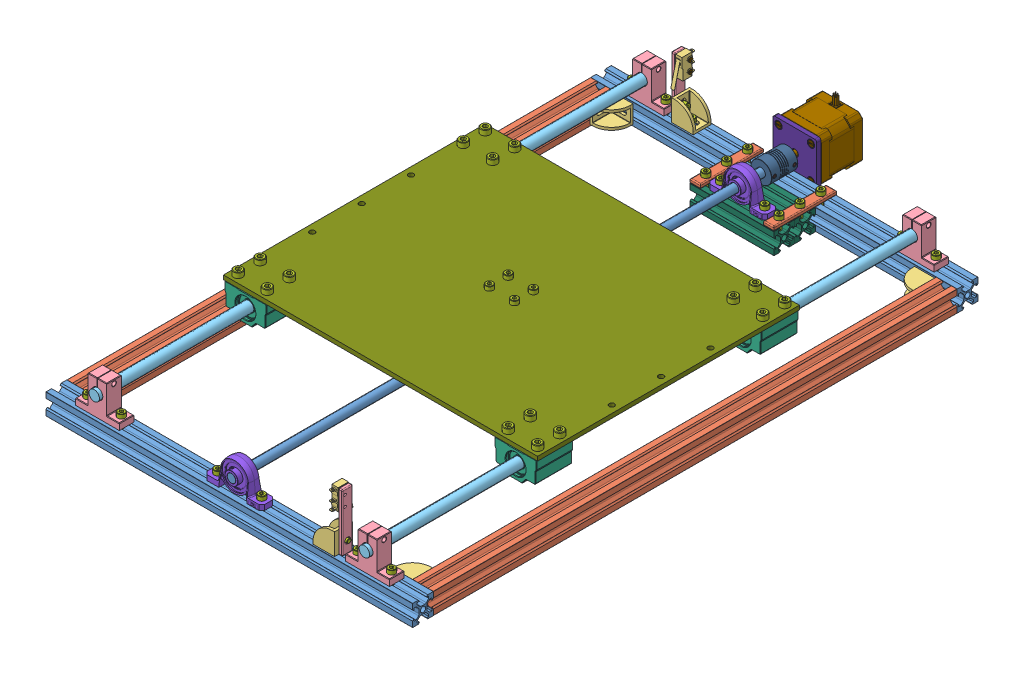
SolidWorks assembly eixoy_assembly, configuration Default. Lengths in mm.
94 component instances, 22 part files, 210 mates.
Components (placement in the parent):
- eixoy_frontal-1: eixoy_frontal [Valor predeterminado] at (179.0484 0.1053 350) x (0 0 -1) z (-1 0 0) size (20 20 350)
- eixoy_frontal-2: eixoy_frontal [Valor predeterminado] at (-170.9516 0.1053 870) x (0 0 -1) z (1 0 0) size (20 20 350)
- eixoy_lateral-1: eixoy_lateral [Valor predeterminado] at (-160.9516 0.1053 360) size (20 20 500)
- eixoy_lateral-2: eixoy_lateral [Valor predeterminado] at (169.0484 0.1053 360) size (20 20 500)
- cantoneira_perfil_2020-1: cantoneira_perfil_2020 [Varsayılan] at (-150.9516 0.1053 360) x (1 0 0) z (0 -1 0) size (20.5 20.5 17)
- cantoneira_perfil_2020-2: cantoneira_perfil_2020 [Varsayılan] at (-150.9516 0.1053 860) x (1 0 0) z (0 1 0) size (20.5 20.5 17)
- cantoneira_perfil_2020-3: cantoneira_perfil_2020 [Varsayılan] at (159.0484 0.1053 360) x (-1 0 0) z (0 1 0) size (20.5 20.5 17)
- cantoneira_perfil_2020-4: cantoneira_perfil_2020 [Varsayılan] at (159.0484 0.1053 860) x (-1 0 0) z (0 -1 0) size (20.5 20.5 17)
- suporte_guia_sk10-1: suporte_guia_sk10 [Default] at (-133.5305 19.8513 863) size (42 32.8 14)
- suporte_guia_sk10-2: suporte_guia_sk10 [Default] at (124.4695 19.8513 863) size (42 32.8 14)
- suporte_guia_sk10-3: suporte_guia_sk10 [Default] at (-133.5305 19.8513 343) size (42 32.8 14)
- suporte_guia_sk10-4: suporte_guia_sk10 [Default] at (124.4695 19.8513 343) size (42 32.8 14)
- eixoy_eixo_linear-1: eixoy_eixo_linear [Default] at (-124.9516 30.1053 340) x (0.995612 0.093577 0) z (0 0 1) size (10 10 540)
- eixoy_eixo_linear-2: eixoy_eixo_linear [Default] at (133.0484 30.1053 340) x (-0.037969 0.999279 0) z (0 0 1) size (10 10 540)
- pillow_block_sc10uu-1: pillow_block_sc10uu [По умолчанию] at (-124.9516 30.1053 718.0563) x (-1 0 0) z (0 0 1) size (40 26 35)
- pillow_block_sc10uu-2: pillow_block_sc10uu [По умолчанию] at (133.0484 30.1053 503.0563) x (-1 0 0) z (0 0 1) size (40 26 35)
- pillow_block_sc10uu-3: pillow_block_sc10uu [По умолчанию] at (-124.9516 30.1053 503.0563) x (-1 0 0) z (0 0 1) size (40 26 35)
- pillow_block_sc10uu-4: pillow_block_sc10uu [По умолчанию] at (133.0484 30.1053 718.0563) x (-1 0 0) z (0 0 1) size (40 26 35)
- socket head cap screw_am-1: socket head cap screw_am [B18.3.1M - 4 x 0.7 x 10 Hex SHCS -- 10NHX] at (117.0484 20.1053 870) x (0 -1 0) z (0 0 1) size (14 7 7)
- socket head cap screw_am-2: socket head cap screw_am [B18.3.1M - 4 x 0.7 x 10 Hex SHCS -- 10NHX] at (149.0484 20.1053 870) x (0 -1 0) z (0 0 1) size (14 7 7)
- socket head cap screw_am-3: socket head cap screw_am [B18.3.1M - 4 x 0.7 x 10 Hex SHCS -- 10NHX] at (-108.9516 20.1053 870) x (0 -1 0) z (0 0 1) size (14 7 7)
- socket head cap screw_am-4: socket head cap screw_am [B18.3.1M - 4 x 0.7 x 10 Hex SHCS -- 10NHX] at (-108.9516 20.1053 350) x (0 -1 0) z (0 0 1) size (14 7 7)
- socket head cap screw_am-5: socket head cap screw_am [B18.3.1M - 4 x 0.7 x 10 Hex SHCS -- 10NHX] at (149.0484 20.1053 350) x (0 -1 0) z (0 0 1) size (14 7 7)
- socket head cap screw_am-6: socket head cap screw_am [B18.3.1M - 4 x 0.7 x 10 Hex SHCS -- 10NHX] at (-140.9516 20.1053 870) x (0 -1 0) z (0 0 1) size (14 7 7)
- socket head cap screw_am-7: socket head cap screw_am [B18.3.1M - 4 x 0.7 x 10 Hex SHCS -- 10NHX] at (117.0484 20.1053 350) x (0 -1 0) z (0 0 1) size (14 7 7)
- socket head cap screw_am-8: socket head cap screw_am [B18.3.1M - 4 x 0.7 x 10 Hex SHCS -- 10NHX] at (-140.9516 20.1053 350) x (0 -1 0) z (0 0 1) size (14 7 7)
- Pillow Block P08-1: Pillow Block P08 [Default] at (4.0484 25.1053 389.6302) size (55 39.88 14.5)
- Pillow Block P08-2: Pillow Block P08 [Default] at (4.0484 25.1053 870) size (55 39.88 14.5)
- motor_nema17_40mm-1: motor_nema17_40mm [По умолчанию] at (4.0484 25.1053 296) x (-1 0 0) z (0 1 0) size (42.3 62 51.35)
- Acople Flexible-1: Acople Flexible [Predeterminado] at (3.1486 26.4664 347) x (-0.025514 0.999674 0) z (0 0 1) size (20.77 20.77 25)
  - Acople FlexibleSLDPRT-1: Acople FlexibleSLDPRT [Predeterminado] at (-1.3837 -0.8648 0) size (20.77 20.77 25)
  - socket set screw cone point_am-7: socket set screw cone point_am [B18.3.6M - M3 x 0.5 x 6 Hex Socket Cone Pt. SS --N] at (-11.2647 -0.8648 22) x (1 0 0) z (0 -0.164849 0.986319) size (6 3 3)
  - socket set screw cone point_am-8: socket set screw cone point_am [B18.3.6M - M3 x 0.5 x 6 Hex Socket Cone Pt. SS --N] at (-11.1909 -0.8648 3) x (1 0 0) z (0 0.00677 0.999977) size (6 3 3)
  - socket set screw cone point_am-9: socket set screw cone point_am [B18.3.6M - M3 x 0.5 x 6 Hex Socket Cone Pt. SS --N] at (-1.3837 -10.7654 3) x (0 1 0) z (-0.345086 0 0.938571) size (6 3 3)
  - socket set screw cone point_am-10: socket set screw cone point_am [B18.3.6M - M3 x 0.5 x 6 Hex Socket Cone Pt. SS --N] at (-1.3837 -10.5992 22) x (0 1 0) z (-0.865685 0 0.500588) size (6 3 3)
- castanha_tr8_2mm-1: castanha_tr8_2mm [Valor predeterminado] at (4.0484 25.1053 599.5563) x (-0.751873 0.659308 0) z (-0.659308 -0.751873 0) size (22 13.71 22)
- suporte_castanha_tr8-1: suporte_castanha_tr8 [Default] at (-13.4516 11.1053 625.5563) x (1 0 0) z (0 1 0) size (35 30 28)
- eixoy_espacador_castanha-1: eixoy_espacador_castanha [Default] at (-13.4516 39.1053 625.5563) x (1 0 0) z (0 1 0) size (35 30 4)
- eixoy_perfil_suporte_mancal-1: eixoy_perfil_suporte_mancal [Valor predeterminado] at (-35.9516 0.1053 370) x (0 0 -1) z (1 0 0) size (20 20 80)
- eixoy_mesa-1: eixoy_mesa [Default] at (154.0484 47.1053 735.5563) x (-1 0 0) z (0 -1 0) size (300 250 4)
- socket head cap screw_am-10: socket head cap screw_am [B18.3.1M - 4 x 0.7 x 10 Hex SHCS -- 10NHX] at (-6.4516 0.1053 332) x (0 0 1) z (1 0 0) size (14 7 7)
- socket head cap screw_am-11: socket head cap screw_am [B18.3.1M - 4 x 0.7 x 10 Hex SHCS -- 10NHX] at (14.5484 0.1053 332) x (0 0 1) z (-1 0 0) size (14 7 7)
- eixoy_suporte_motor-3: eixoy_suporte_motor [Default] at (25.0484 -9.8947 340) x (-1 0 0) z (0 0 -1) size (42 56 4)
- flat head screw_am-1: flat head screw_am [B18.6.7M - M3 x 0.5 x 8 Slotted FHMS --8N] at (-11.4516 9.6053 340) x (0 0 -1) z (1 0 0) size (8 5.5 5.41)
- flat head screw_am-2: flat head screw_am [B18.6.7M - M3 x 0.5 x 8 Slotted FHMS --8N] at (-11.4516 40.6053 340) x (0 0 -1) z (1 0 0) size (8 5.5 5.41)
- flat head screw_am-3: flat head screw_am [B18.6.7M - M3 x 0.5 x 8 Slotted FHMS --8N] at (19.5484 9.6053 340) x (0 0 -1) z (1 0 0) size (8 5.5 5.41)
- flat head screw_am-4: flat head screw_am [B18.6.7M - M3 x 0.5 x 8 Slotted FHMS --8N] at (19.5484 40.6053 340) x (0 0 -1) z (1 0 0) size (8 5.5 5.41)
- eixoy_perfil_suporte_mancal-2: eixoy_perfil_suporte_mancal [Valor predeterminado] at (-35.9516 0.1053 390) x (0 0 -1) z (1 0 0) size (20 20 80)
- eixoy_fuso-1: eixoy_fuso [Default] at (4.0484 25.1053 365.95) x (-0.063938 0.997954 0) z (0 0 1) size (8 8 512)
- eixoy_chapa_suporte_mancal-1: eixoy_chapa_suporte_mancal [Default] at (-35.9516 14.1053 340) x (1 0 0) z (0 -1 0) size (10 60 4)
- eixoy_chapa_suporte_mancal-2: eixoy_chapa_suporte_mancal [Default] at (34.0484 14.1053 340) x (1 0 0) z (0 -1 0) size (10 60 4)
- socket head cap screw_am-12: socket head cap screw_am [B18.3.1M - 4 x 0.7 x 10 Hex SHCS -- 10NHX] at (25.0484 19.1053 389.6302) x (0 -1 0) z (0 0 1) size (14 7 7)
- socket head cap screw_am-13: socket head cap screw_am [B18.3.1M - 4 x 0.7 x 10 Hex SHCS -- 10NHX] at (39.0484 18.1053 350) x (0 -1 0) z (-0.924225 0 0.381849) size (14 7 7)
- socket head cap screw_am-14: socket head cap screw_am [B18.3.1M - 4 x 0.7 x 10 Hex SHCS -- 10NHX] at (-30.9516 18.1053 350) x (0 -1 0) z (0 0 1) size (14 7 7)
- socket head cap screw_am-15: socket head cap screw_am [B18.3.1M - 4 x 0.7 x 10 Hex SHCS -- 10NHX] at (39.0484 18.1053 390) x (0 -1 0) z (0 0 1) size (14 7 7)
- socket head cap screw_am-16: socket head cap screw_am [B18.3.1M - 4 x 0.7 x 10 Hex SHCS -- 10NHX] at (39.0484 18.1053 370) x (0 -1 0) z (0 0 1) size (14 7 7)
- socket head cap screw_am-17: socket head cap screw_am [B18.3.1M - 4 x 0.7 x 10 Hex SHCS -- 10NHX] at (-16.9516 19.1053 389.6302) x (0 -1 0) z (0 0 1) size (14 7 7)
- socket head cap screw_am-18: socket head cap screw_am [B18.3.1M - 4 x 0.7 x 10 Hex SHCS -- 10NHX] at (-30.9516 18.1053 390) x (0 -1 0) z (0 0 1) size (14 7 7)
- socket head cap screw_am-19: socket head cap screw_am [B18.3.1M - 4 x 0.7 x 10 Hex SHCS -- 10NHX] at (-30.9516 18.1053 370) x (0 -1 0) z (0 0 1) size (14 7 7)
- socket head cap screw_am-20: socket head cap screw_am [B18.3.1M - 4 x 0.7 x 10 Hex SHCS -- 10NHX] at (25.0484 19.1053 870) x (0 -1 0) z (0 0 1) size (14 7 7)
- socket head cap screw_am-21: socket head cap screw_am [B18.3.1M - 4 x 0.7 x 10 Hex SHCS -- 10NHX] at (-16.9516 19.1053 870) x (0 -1 0) z (0 0 1) size (14 7 7)
- switch_fim_de_curso_KW11-3Z-5-2: switch_fim_de_curso_KW11-3Z-5 [Default] at (96.8484 45.2053 875.4) x (0 1 0) z (0 0 -1) size (25.09 6.4 19.9)
- eixoy_suporte_fim_curso-1: eixoy_suporte_fim_curso [Default] at (-94.9516 65.1053 355) x (0 0 -1) z (-1 0 0) size (10 55 4)
- switch_fim_de_curso_KW11-3Z-5-3: switch_fim_de_curso_KW11-3Z-5 [Default] at (-88.7516 45.2053 344.6) x (0 1 0) z (0 0 1) size (25.09 6.4 19.9)
- flat head screw_am-5: flat head screw_am [B18.6.7M - M2 x 0.4 x 10 Slotted FHMS --10N] at (-87.5516 50.2053 347.6) x (-1 0 0) z (0 0.022385 0.999749) size (10 3.8 3.73)
- flat head screw_am-6: flat head screw_am [B18.6.7M - M2 x 0.4 x 10 Slotted FHMS --10N] at (-87.5516 60.1053 347.6) x (-1 0 0) z (0 -0.689904 -0.723901) size (10 3.8 3.73)
- cantoneira_perfil_2020-5: cantoneira_perfil_2020 [Varsayılan] at (-94.9516 10.1053 350) size (20.5 20.5 17)
- socket head cap screw_am-22: socket head cap screw_am [B18.3.1M - 4 x 0.7 x 10 Hex SHCS -- 10NHX] at (-84.0639 16.6053 350.75) x (0 -1 0) z (-0.654967 0 0.755658) size (14 7 7)
- socket head cap screw_am-23: socket head cap screw_am [B18.3.1M - 4 x 0.7 x 8 Hex SHCS -- 8NHX] at (-88.4516 21.3124 350) x (-1 0 0) z (0 0 1) size (12 7 7)
- eixoy_suporte_fim_curso-2: eixoy_suporte_fim_curso [Default] at (103.0484 65.1053 865) x (0 0 1) z (1 0 0) size (10 55 4)
- flat head screw_am-7: flat head screw_am [B18.6.7M - M2 x 0.4 x 10 Slotted FHMS --10N] at (95.6484 50.2053 872.4) size (10 3.8 3.73)
- flat head screw_am-8: flat head screw_am [B18.6.7M - M2 x 0.4 x 10 Slotted FHMS --10N] at (95.6484 60.1053 872.4) x (1 0 0) z (0 0.537114 0.843509) size (10 3.8 3.73)
- cantoneira_perfil_2020-6: cantoneira_perfil_2020 [Varsayılan] at (103.0484 10.1053 870) x (-1 0 0) z (0 0 -1) size (20.5 20.5 17)
- socket head cap screw_am-25: socket head cap screw_am [B18.3.1M - 4 x 0.7 x 8 Hex SHCS -- 8NHX] at (96.5484 21.3124 870) size (12 7 7)
- socket head cap screw_am-28: socket head cap screw_am [B18.3.1M - 5 x 0.8 x 10 Hex SHCS -- 10NHX] at (-110.9516 52.1053 707.5563) x (0 -1 0) z (0 0 1) size (15 8.5 8.5)
- socket head cap screw_am-29: socket head cap screw_am [B18.3.1M - 5 x 0.8 x 10 Hex SHCS -- 10NHX] at (-110.9516 52.1053 728.5563) x (0 -1 0) z (0 0 1) size (15 8.5 8.5)
- socket head cap screw_am-30: socket head cap screw_am [B18.3.1M - 5 x 0.8 x 10 Hex SHCS -- 10NHX] at (-138.9516 52.1053 707.5563) x (0 -1 0) z (0 0 1) size (15 8.5 8.5)
- socket head cap screw_am-31: socket head cap screw_am [B18.3.1M - 5 x 0.8 x 10 Hex SHCS -- 10NHX] at (-138.9516 52.1053 728.5563) x (0 -1 0) z (0 0 1) size (15 8.5 8.5)
- socket head cap screw_am-32: socket head cap screw_am [B18.3.1M - 5 x 0.8 x 10 Hex SHCS -- 10NHX] at (119.0484 52.1053 707.5563) x (0 -1 0) z (0 0 1) size (15 8.5 8.5)
- socket head cap screw_am-33: socket head cap screw_am [B18.3.1M - 5 x 0.8 x 10 Hex SHCS -- 10NHX] at (119.0484 52.1053 728.5563) x (0 -1 0) z (0 0 1) size (15 8.5 8.5)
- socket head cap screw_am-34: socket head cap screw_am [B18.3.1M - 5 x 0.8 x 10 Hex SHCS -- 10NHX] at (147.0484 52.1053 728.5563) x (0 -1 0) z (0 0 1) size (15 8.5 8.5)
- socket head cap screw_am-35: socket head cap screw_am [B18.3.1M - 5 x 0.8 x 10 Hex SHCS -- 10NHX] at (147.0484 52.1053 707.5563) x (0 -1 0) z (0 0 1) size (15 8.5 8.5)
- socket head cap screw_am-36: socket head cap screw_am [B18.3.1M - 5 x 0.8 x 10 Hex SHCS -- 10NHX] at (119.0484 52.1053 513.5563) x (0 -1 0) z (0 0 1) size (15 8.5 8.5)
- socket head cap screw_am-37: socket head cap screw_am [B18.3.1M - 5 x 0.8 x 10 Hex SHCS -- 10NHX] at (119.0484 52.1053 492.5563) x (0 -1 0) z (0 0 1) size (15 8.5 8.5)
- socket head cap screw_am-38: socket head cap screw_am [B18.3.1M - 5 x 0.8 x 10 Hex SHCS -- 10NHX] at (147.0484 52.1053 492.5563) x (0 -1 0) z (0 0 1) size (15 8.5 8.5)
- socket head cap screw_am-39: socket head cap screw_am [B18.3.1M - 5 x 0.8 x 10 Hex SHCS -- 10NHX] at (147.0484 52.1053 513.5563) x (0 -1 0) z (0 0 1) size (15 8.5 8.5)
- socket head cap screw_am-40: socket head cap screw_am [B18.3.1M - 5 x 0.8 x 10 Hex SHCS -- 10NHX] at (-138.9516 52.1053 492.5563) x (0 -1 0) z (0 0 1) size (15 8.5 8.5)
- socket head cap screw_am-41: socket head cap screw_am [B18.3.1M - 5 x 0.8 x 10 Hex SHCS -- 10NHX] at (-110.9516 52.1053 492.5563) x (0 -1 0) z (0 0 1) size (15 8.5 8.5)
- socket head cap screw_am-42: socket head cap screw_am [B18.3.1M - 5 x 0.8 x 10 Hex SHCS -- 10NHX] at (-110.9516 52.1053 513.5563) x (0 -1 0) z (0 0 1) size (15 8.5 8.5)
- socket head cap screw_am-43: socket head cap screw_am [B18.3.1M - 5 x 0.8 x 10 Hex SHCS -- 10NHX] at (-138.9516 52.1053 513.5563) x (0 -1 0) z (0 0 1) size (15 8.5 8.5)
- socket head cap screw_am-44: socket head cap screw_am [B18.3.1M - 4 x 0.7 x 8 Hex SHCS -- 8NHX] at (16.0484 51.1053 601.5563) x (0 -1 0) z (0 0 1) size (12 7 7)
- socket head cap screw_am-45: socket head cap screw_am [B18.3.1M - 4 x 0.7 x 8 Hex SHCS -- 8NHX] at (-7.9516 51.1053 601.5563) x (0 -1 0) z (0 0 1) size (12 7 7)
- socket head cap screw_am-46: socket head cap screw_am [B18.3.1M - 4 x 0.7 x 8 Hex SHCS -- 8NHX] at (-7.9516 51.1053 619.5563) x (0 -1 0) z (0 0 1) size (12 7 7)
- socket head cap screw_am-47: socket head cap screw_am [B18.3.1M - 4 x 0.7 x 8 Hex SHCS -- 8NHX] at (16.0484 51.1053 619.5563) x (0 -1 0) z (0 0 1) size (12 7 7)
Mates (geometry in assembly coordinates):
- Coincident1: coincident aligned: plane of eixoy_frontal-2 through (179.0484 10.1053 865.4) normal (0 1 0); plane of eixoy_lateral-1 through (-156.3516 10.1053 860) normal (0 1 0)
- Coincident2: coincident anti-aligned: plane of eixoy_frontal-2 through (179.0484 9.9053 860) normal (0 0 -1); plane of eixoy_lateral-1 through (-164.5344 -8.5947 860) normal (0 0 1)
- Coincident3: coincident aligned: plane of eixoy_frontal-2 through (-170.9516 -8.5947 873.5828) normal (-1 0 0); plane of eixoy_lateral-1 through (-170.9516 9.9053 860) normal (-1 0 0)
- Coincident4: coincident aligned: plane of eixoy_frontal-2 through (179.0484 -8.5947 873.5828) normal (1 0 0); plane of eixoy_lateral-2 through (179.0484 9.9053 860) normal (1 0 0)
- Coincident5: coincident aligned: plane of eixoy_frontal-2 through (179.0484 10.1053 874.6) normal (0 1 0); plane of eixoy_lateral-2 through (173.6484 10.1053 860) normal (0 1 0)
- Coincident6: coincident anti-aligned: plane of eixoy_frontal-2 through (179.0484 9.9053 860) normal (0 0 -1); plane of eixoy_lateral-2 through (165.4656 -8.5947 860) normal (0 0 1)
- Coincident7: coincident anti-aligned: plane of eixoy_frontal-1 through (-170.9516 9.9053 360) normal (0 0 1); plane of eixoy_lateral-2 through (165.4656 -8.5947 360) normal (0 0 -1)
- Coincident8: coincident aligned: plane of eixoy_frontal-1 through (179.0484 8.8053 353.5828) normal (1 0 0); plane of eixoy_lateral-2 through (179.0484 9.9053 860) normal (1 0 0)
- Coincident9: coincident aligned: plane of eixoy_frontal-1 through (-170.9516 10.1053 354.6) normal (0 1 0); plane of eixoy_lateral-2 through (164.4484 10.1053 860) normal (0 1 0)
- Coincident10: coincident anti-aligned: plane of eixoy_lateral-1 through (-150.9516 9.9053 860) normal (1 0 0); plane of cantoneira_perfil_2020-1 through (-150.9516 -8.3947 360) normal (-1 0 0)
- Coincident11: coincident aligned: plane of cantoneira_perfil_2020-1 through (-150.9516 -8.3947 360) normal (-1 0 0); plane of cantoneira_perfil_2020-2 through (-150.9516 8.6053 860) normal (-1 0 0)
- Coincident12: coincident anti-aligned: plane of eixoy_frontal-2 through (179.0484 9.9053 860) normal (0 0 -1); plane of cantoneira_perfil_2020-2 through (-130.4516 8.6053 860) normal (0 0 1)
- Coincident13: coincident anti-aligned: plane of eixoy_frontal-1 through (-170.9516 9.9053 360) normal (0 0 1); plane of cantoneira_perfil_2020-1 through (-130.4516 -8.3947 360) normal (0 0 -1)
- Coincident14: coincident anti-aligned: plane of eixoy_lateral-2 through (159.0484 9.9053 860) normal (-1 0 0); plane of cantoneira_perfil_2020-3 through (159.0484 8.6053 360) normal (1 0 0)
- Coincident15: coincident anti-aligned: plane of eixoy_frontal-1 through (-170.9516 9.9053 360) normal (0 0 1); plane of cantoneira_perfil_2020-3 through (138.5484 8.6053 360) normal (0 0 -1)
- Coincident16: coincident aligned: plane of cantoneira_perfil_2020-1 through (-150.9516 8.6053 360) normal (0 1 0); plane of cantoneira_perfil_2020-3 through (159.0484 8.6053 360) normal (0 1 0)
- Coincident17: coincident aligned: plane of cantoneira_perfil_2020-1 through (-150.9516 8.6053 360) normal (0 1 0); plane of cantoneira_perfil_2020-2 through (-150.9516 8.6053 860) normal (0 1 0)
- Coincident19: coincident anti-aligned: plane of eixoy_frontal-2 through (179.0484 9.9053 860) normal (0 0 -1); plane of cantoneira_perfil_2020-4 through (138.5484 -8.3947 860) normal (0 0 1)
- Coincident20: coincident aligned: plane of cantoneira_perfil_2020-2 through (-150.9516 8.6053 860) normal (0 1 0); plane of cantoneira_perfil_2020-4 through (159.0484 8.6053 860) normal (0 1 0)
- Coincident21: coincident anti-aligned: plane of eixoy_lateral-2 through (159.0484 9.9053 860) normal (-1 0 0); plane of cantoneira_perfil_2020-4 through (159.0484 -8.3947 860) normal (1 0 0)
- Distance1: distance = 1.5 mm aligned: plane of cantoneira_perfil_2020-4 through (159.0484 8.6053 860) normal (0 1 0); plane of eixoy_lateral-2 through (164.4484 10.1053 860) normal (0 1 0)
- Concentric1: concentric anti-aligned: cylinder of suporte_guia_sk10-1 through (-124.9516 30.1053 863) axis (0 0 1) radius 5; cylinder of eixoy_eixo_linear-1 through (-124.9516 30.1053 880) axis (0 0 -1) radius 5
- Concentric2: concentric anti-aligned: cylinder of suporte_guia_sk10-3 through (-124.9516 30.1053 343) axis (0 0 1) radius 5; cylinder of eixoy_eixo_linear-1 through (-124.9516 30.1053 880) axis (0 0 -1) radius 5
- Concentric3: concentric anti-aligned: cylinder of suporte_guia_sk10-2 through (133.0484 30.1053 863) axis (0 0 1) radius 5; cylinder of eixoy_eixo_linear-2 through (133.0484 30.1053 880) axis (0 0 -1) radius 5
- Concentric4: concentric anti-aligned: cylinder of suporte_guia_sk10-4 through (133.0484 30.1053 343) axis (0 0 1) radius 5; cylinder of eixoy_eixo_linear-2 through (133.0484 30.1053 880) axis (0 0 -1) radius 5
- Distance2: distance = 3 mm aligned: plane of suporte_guia_sk10-1 through (-133.5305 19.8513 877) normal (0 0 1); plane of eixoy_frontal-2 through (179.0484 9.9053 880) normal (0 0 1)
- Coincident24: coincident anti-aligned: plane of eixoy_frontal-2 through (179.0484 10.1053 874.6) normal (0 1 0); plane of suporte_guia_sk10-1 through (-145.9516 10.1053 877) normal (0 -1 0)
- Coincident25: coincident aligned: plane of suporte_guia_sk10-4 through (112.0484 10.1053 357) normal (0 -1 0); plane of suporte_guia_sk10-2 through (112.0484 10.1053 877) normal (0 -1 0)
- Coincident26: coincident aligned: plane of suporte_guia_sk10-1 through (-133.5305 19.8513 877) normal (0 0 1); plane of suporte_guia_sk10-2 through (124.4695 19.8513 877) normal (0 0 1)
- Coincident27: coincident aligned: plane of suporte_guia_sk10-2 through (112.0484 10.1053 877) normal (0 -1 0); plane of suporte_guia_sk10-4 through (112.0484 10.1053 357) normal (0 -1 0)
- Coincident28: coincident aligned: plane of suporte_guia_sk10-3 through (-145.9516 10.1053 357) normal (0 -1 0); plane of suporte_guia_sk10-4 through (112.0484 10.1053 357) normal (0 -1 0)
- Coincident29: coincident aligned: plane of suporte_guia_sk10-1 through (-145.9516 10.1053 877) normal (0 -1 0); plane of suporte_guia_sk10-3 through (-145.9516 10.1053 357) normal (0 -1 0)
- Coincident30: coincident aligned: plane of suporte_guia_sk10-3 through (-133.5305 19.8513 343) normal (0 0 -1); plane of suporte_guia_sk10-4 through (124.4695 19.8513 343) normal (0 0 -1)
- Distance3: distance = 3 mm aligned: plane of suporte_guia_sk10-4 through (124.4695 19.8513 343) normal (0 0 -1); plane of eixoy_frontal-1 through (-170.9516 9.9053 340) normal (0 0 -1)
- Coincident32: coincident aligned: plane of eixoy_frontal-1 through (-170.9516 9.9053 340) normal (0 0 -1); plane of eixoy_eixo_linear-1 through (-124.9516 30.1053 340) normal (0 0 -1)
- Coincident33: coincident aligned: plane of eixoy_frontal-1 through (-170.9516 9.9053 340) normal (0 0 -1); plane of eixoy_eixo_linear-2 through (133.0484 30.1053 340) normal (0 0 -1)
- Distance5: distance = 25 mm aligned: plane of suporte_guia_sk10-1 through (-145.9516 16.1053 877) normal (-1 0 0); plane of eixoy_frontal-2 through (-170.9516 -8.5947 873.5828) normal (-1 0 0)
- Distance6: distance = 25 mm aligned: plane of suporte_guia_sk10-2 through (154.0484 16.1053 877) normal (1 0 0); plane of eixoy_frontal-2 through (179.0484 -8.5947 873.5828) normal (1 0 0)
- Coincident37: coincident aligned: plane of pillow_block_sc10uu-1 through (-113.5039 43.1053 735.5563) normal (0 1 0); plane of pillow_block_sc10uu-3 through (-113.5039 43.1053 520.5563) normal (0 1 0)
- Coincident38: coincident aligned: plane of pillow_block_sc10uu-3 through (-113.5039 43.1053 520.5563) normal (0 1 0); plane of pillow_block_sc10uu-4 through (144.4961 43.1053 735.5563) normal (0 1 0)
- Coincident39: coincident aligned: plane of pillow_block_sc10uu-2 through (144.4961 43.1053 520.5563) normal (0 1 0); plane of pillow_block_sc10uu-4 through (144.4961 43.1053 735.5563) normal (0 1 0)
- Concentric5: concentric aligned: cylinder of eixoy_eixo_linear-2 through (133.0484 30.1053 880) axis (0 0 -1) radius 5; cylinder of pillow_block_sc10uu-2 through (133.0484 30.1053 517.5563) axis (0 0 -1) radius 5
- Concentric6: concentric aligned: cylinder of eixoy_eixo_linear-2 through (133.0484 30.1053 880) axis (0 0 -1) radius 5; cylinder of pillow_block_sc10uu-4 through (133.0484 30.1053 732.5563) axis (0 0 -1) radius 5
- Concentric7: concentric aligned: cylinder of eixoy_eixo_linear-1 through (-124.9516 30.1053 880) axis (0 0 -1) radius 5; cylinder of pillow_block_sc10uu-1 through (-124.9516 30.1053 732.5563) axis (0 0 -1) radius 5
- Concentric8: concentric aligned: cylinder of eixoy_eixo_linear-1 through (-124.9516 30.1053 880) axis (0 0 -1) radius 5; cylinder of pillow_block_sc10uu-3 through (-124.9516 30.1053 517.5563) axis (0 0 -1) radius 5
- Coincident40: coincident aligned: plane of pillow_block_sc10uu-2 through (133.0484 30.1053 520.5563) normal (0 0 1); plane of pillow_block_sc10uu-3 through (-124.9516 30.1053 520.5563) normal (0 0 1)
- Coincident41: coincident aligned: plane of pillow_block_sc10uu-1 through (-124.9516 30.1053 700.5563) normal (0 0 -1); plane of pillow_block_sc10uu-4 through (133.0484 30.1053 700.5563) normal (0 0 -1)
- Coincident42: coincident aligned: plane of suporte_guia_sk10-1 through (-145.9516 16.1053 877) normal (0 1 0); circle of parafuso_allen_m4x10-1
- Coincident43: coincident aligned: plane of socket head cap screw_am-4 through (-105.4516 16.1053 350) normal (0 -1 0); plane of socket head cap screw_am-8 through (-137.4516 16.1053 350) normal (0 -1 0)
- Coincident44: coincident aligned: plane of socket head cap screw_am-4 through (-105.4516 16.1053 350) normal (0 -1 0); plane of socket head cap screw_am-7 through (120.5484 16.1053 350) normal (0 -1 0)
- Coincident45: coincident aligned: plane of socket head cap screw_am-5 through (152.5484 16.1053 350) normal (0 -1 0); plane of socket head cap screw_am-7 through (120.5484 16.1053 350) normal (0 -1 0)
- Coincident46: coincident aligned: plane of socket head cap screw_am-5 through (152.5484 16.1053 350) normal (0 -1 0); plane of socket head cap screw_am-6 through (-137.4516 16.1053 870) normal (0 -1 0)
- Coincident47: coincident aligned: plane of socket head cap screw_am-3 through (-105.4516 16.1053 870) normal (0 -1 0); plane of socket head cap screw_am-6 through (-137.4516 16.1053 870) normal (0 -1 0)
- Coincident48: coincident aligned: plane of socket head cap screw_am-2 through (152.5484 16.1053 870) normal (0 -1 0); plane of socket head cap screw_am-3 through (-105.4516 16.1053 870) normal (0 -1 0)
- Coincident49: coincident anti-aligned: plane of suporte_guia_sk10-2 through (142.0484 16.1053 877) normal (0 1 0); plane of socket head cap screw_am-2 through (152.5484 16.1053 870) normal (0 -1 0)
- Concentric9: concentric aligned: circle of suporte_guia_sk10-2; cylinder of socket head cap screw_am-2 through (149.0484 51.8553 870) axis (0 1 0) radius 2
- Concentric10: concentric aligned: circle of suporte_guia_sk10-2; cylinder of socket head cap screw_am-1 through (117.0484 51.8553 870) axis (0 1 0) radius 2
- Concentric11: concentric anti-aligned: cylinder of suporte_guia_sk10-1 through (-108.9516 35.1053 870) axis (0 -1 0) radius 2.5; cylinder of socket head cap screw_am-3 through (-108.9516 51.8553 870) axis (0 1 0) radius 2
- Concentric12: concentric anti-aligned: cylinder of suporte_guia_sk10-1 through (-140.9516 35.1053 870) axis (0 -1 0) radius 2.5; cylinder of socket head cap screw_am-6 through (-140.9516 51.8553 870) axis (0 1 0) radius 2
- Concentric13: concentric anti-aligned: cylinder of suporte_guia_sk10-4 through (149.0484 35.1053 350) axis (0 -1 0) radius 2.5; cylinder of socket head cap screw_am-5 through (149.0484 51.8553 350) axis (0 1 0) radius 2
- Concentric14: concentric aligned: circle of suporte_guia_sk10-4; cylinder of socket head cap screw_am-7 through (117.0484 51.8553 350) axis (0 1 0) radius 2
- Concentric15: concentric aligned: circle of suporte_guia_sk10-3; cylinder of socket head cap screw_am-4 through (-108.9516 51.8553 350) axis (0 1 0) radius 2
- Concentric16: concentric anti-aligned: cylinder of suporte_guia_sk10-3 through (-140.9516 35.1053 350) axis (0 -1 0) radius 2.5; cylinder of socket head cap screw_am-8 through (-140.9516 51.8553 350) axis (0 1 0) radius 2
- Distance7: distance = 250 mm anti-aligned: plane of pillow_block_sc10uu-2 through (133.0484 30.1053 485.5563) normal (0 0 -1); plane of pillow_block_sc10uu-4 through (133.0484 30.1053 735.5563) normal (0 0 1)
- Coincident52: coincident aligned: plane of Pillow Block P08-1 through (4.0484 10.1053 389.6302) normal (0 -1 0); plane of Pillow Block P08-2 through (4.0484 10.1053 870) normal (0 -1 0)
- Coincident53: coincident anti-aligned: plane of eixoy_frontal-1 through (-170.9516 10.1053 354.6) normal (0 1 0); plane of Pillow Block P08-1 through (4.0484 10.1053 389.6302) normal (0 -1 0)
- Distance9: distance = 3.5 mm aligned: plane of Pillow Block P08-2 through (4.0484 25.1053 876.5) normal (0 0 1); plane of eixoy_frontal-2 through (179.0484 9.9053 880) normal (0 0 1)
- Coincident56: coincident aligned: cylinder of motor_nema17_40mm-1 through (4.0484 25.1053 358) axis (0 0 -1) radius 2.5; circle of Acople Flexible-1/Acople FlexibleSLDPRT-1
- Distance10: distance = 4 mm: plane of Acople Flexible-1/Acople FlexibleSLDPRT-1 through (4.0484 25.1053 347) normal (0 0 -1); line of motor_nema17_40mm-1 through (1.6076 24.5645 343) axis (0.412738 0.91085 0)
- Concentric17: concentric anti-aligned: cylinder of Pillow Block P08-1 through (4.0484 25.1053 381.393) axis (0 0 -1) radius 4; cylinder of Acople Flexible-1/Acople FlexibleSLDPRT-1 through (4.0484 25.1053 354) axis (0 0 1) radius 4
- Coincident58: coincident aligned: plane of Pillow Block P08-1 through (-23.4516 25.1053 396.1302) normal (-1 0 0); plane of Pillow Block P08-2 through (-23.4516 25.1053 876.5) normal (-1 0 0)
- Distance11: distance = 147.5 mm aligned: plane of Pillow Block P08-2 through (31.5484 25.1053 876.5) normal (1 0 0); plane of eixoy_frontal-2 through (179.0484 -8.5947 873.5828) normal (1 0 0)
- Parallel1: parallel aligned: plane of eixoy_frontal-1 through (-170.9516 10.1053 354.6) normal (0 1 0); plane of motor_nema17_40mm-1 through (4.0484 46.1053 336) normal (0 1 0)
- Concentric18: concentric aligned: circle of Acople Flexible-1/Acople FlexibleSLDPRT-1; circle of castanha_tr8_2mm-1
- Concentric19: concentric anti-aligned: cylinder of castanha_tr8_2mm-1 through (4.0484 25.1053 609.5563) axis (0 0 -1) radius 5; cylinder of suporte_castanha_tr8-1 through (4.0484 25.1053 617.5563) axis (0 0 1) radius 7
- Parallel2: parallel aligned: cylinder of castanha_tr8_2mm-1 through (3.493 33.5721 609.5573) axis (0 0 -1) radius 1.75; cylinder of suporte_castanha_tr8-1 through (4.0484 33.1053 609.5563) axis (0 0 -1) radius 1.5
- Parallel3: parallel aligned: cylinder of castanha_tr8_2mm-1 through (4.6038 16.6385 609.5573) axis (0 0 -1) radius 1.75; cylinder of suporte_castanha_tr8-1 through (4.0484 17.1053 609.5563) axis (0 0 -1) radius 1.5
- Coincident60: coincident anti-aligned: plane of castanha_tr8_2mm-1 through (4.0484 25.1053 599.5563) normal (0 0 1); plane of suporte_castanha_tr8-1 through (4.0484 25.1053 599.5563) normal (0 0 -1)
- Parallel4: parallel aligned: plane of eixoy_lateral-1 through (-165.5516 10.1053 860) normal (0 1 0); plane of suporte_castanha_tr8-1 through (-13.4516 39.1053 625.5563) normal (0 1 0)
- Coincident62: coincident aligned: plane of suporte_castanha_tr8-1 through (21.5484 39.1053 625.5563) normal (1 0 0); plane of eixoy_espacador_castanha-1 through (21.5484 43.1053 625.5563) normal (1 0 0)
- Coincident63: coincident aligned: plane of suporte_castanha_tr8-1 through (-13.4516 39.1053 625.5563) normal (0 0 1); plane of eixoy_espacador_castanha-1 through (-13.4516 43.1053 625.5563) normal (0 0 1)
- Coincident64: coincident anti-aligned: plane of suporte_castanha_tr8-1 through (-13.4516 39.1053 625.5563) normal (0 1 0); plane of eixoy_espacador_castanha-1 through (-13.4516 39.1053 625.5563) normal (0 -1 0)
- Distance12: distance = 4 mm anti-aligned: plane of motor_nema17_40mm-1 through (4.0484 25.1053 336) normal (0 0 1); plane of eixoy_frontal-1 through (-170.9516 9.9053 340) normal (0 0 -1)
- Coincident66: coincident aligned: plane of eixoy_frontal-1 through (-170.9516 10.1053 354.6) normal (0 1 0); plane of eixoy_perfil_suporte_mancal-1 through (44.0484 10.1053 365.4) normal (0 1 0)
- Coincident67: coincident anti-aligned: plane of eixoy_frontal-1 through (-170.9516 9.9053 360) normal (0 0 1); plane of eixoy_perfil_suporte_mancal-1 through (44.0484 9.9053 360) normal (0 0 -1)
- Distance13: distance = 135 mm aligned: plane of eixoy_perfil_suporte_mancal-1 through (-35.9516 -8.5947 373.5828) normal (-1 0 0); plane of eixoy_frontal-1 through (-170.9516 8.8053 353.5828) normal (-1 0 0)
- Distance14: distance = 110 mm aligned: plane of suporte_castanha_tr8-1 through (-13.4516 39.1053 595.5563) normal (0 0 -1); plane of pillow_block_sc10uu-2 through (133.0484 30.1053 485.5563) normal (0 0 -1)
- Coincident73: coincident anti-aligned: plane of pillow_block_sc10uu-3 through (-113.5039 43.1053 520.5563) normal (0 1 0); plane of eixoy_mesa-1 through (154.0484 43.1053 735.5563) normal (0 -1 0)
- Coincident74: coincident aligned: plane of pillow_block_sc10uu-3 through (-124.9516 30.1053 485.5563) normal (0 0 -1); plane of eixoy_mesa-1 through (154.0484 43.1053 485.5563) normal (0 0 -1)
- Distance15: distance = 1 mm aligned: plane of eixoy_mesa-1 through (154.0484 43.1053 735.5563) normal (1 0 0); plane of pillow_block_sc10uu-2 through (153.0484 36.3061 520.5563) normal (1 0 0)
- Concentric29: concentric aligned: cylinder of socket head cap screw_am-11 through (14.5484 0.1053 300.25) axis (0 0 -1) radius 2; cylinder of eixoy_suporte_motor-3 through (14.5484 0.1053 346) axis (0 0 -1) radius 2.5
- Concentric30: concentric aligned: cylinder of socket head cap screw_am-10 through (-6.4516 0.1053 300.25) axis (0 0 -1) radius 2; circle of eixoy_suporte_motor-3
- Tangent5: tangent aligned: plane of socket head cap screw_am-10 through (-6.4516 -3.3947 336) normal (0 0 1); torus of socket head cap screw_am-11
- Coincident84: coincident anti-aligned: plane of socket head cap screw_am-11 through (14.5484 3.6053 336) normal (0 0 1); plane of eixoy_suporte_motor-3 through (25.0484 -9.8947 336) normal (0 0 -1)
- Coincident85: coincident aligned: plane of eixoy_frontal-1 through (-170.9516 -9.8947 345.4) normal (0 -1 0); plane of eixoy_suporte_motor-3 through (25.0484 -9.8947 336) normal (0 -1 0)
- Concentric31: concentric aligned: cylinder of motor_nema17_40mm-1 through (4.0484 25.1053 358) axis (0 0 -1) radius 2.5; circle of eixoy_suporte_motor-3
- Coincident86: coincident aligned: plane of flat head screw_am-2 through (-11.4516 42.1053 332) normal (0 0 -1); plane of flat head screw_am-3 through (19.5484 11.1053 332) normal (0 0 -1)
- Coincident87: coincident aligned: plane of flat head screw_am-2 through (-11.4516 42.1053 332) normal (0 0 -1); plane of flat head screw_am-4 through (19.5484 42.1053 332) normal (0 0 -1)
- Coincident88: coincident aligned: plane of flat head screw_am-1 through (-11.4516 11.1053 332) normal (0 0 -1); plane of flat head screw_am-4 through (19.5484 42.1053 332) normal (0 0 -1)
- Coincident89: coincident aligned: plane of eixoy_suporte_motor-3 through (25.0484 -9.8947 340) normal (0 0 1); plane of flat head screw_am-3 through (19.5484 9.6053 340) normal (0 0 1)
- Concentric32: concentric aligned: circle of eixoy_suporte_motor-3; cylinder of flat head screw_am-4 through (19.5484 40.6053 346.35) axis (0 0 1) radius 1.5
- Concentric33: concentric aligned: circle of eixoy_suporte_motor-3; cylinder of flat head screw_am-2 through (-11.4516 40.6053 346.35) axis (0 0 1) radius 1.5
- Concentric34: concentric aligned: circle of eixoy_suporte_motor-3; cylinder of flat head screw_am-3 through (19.5484 9.6053 346.35) axis (0 0 1) radius 1.5
- Concentric35: concentric aligned: cylinder of eixoy_suporte_motor-3 through (-11.4516 9.6053 338) axis (0 0 1) radius 3.5; cylinder of flat head screw_am-1 through (-11.4516 9.6053 346.35) axis (0 0 1) radius 1.5
- Coincident90: coincident anti-aligned: plane of eixoy_frontal-1 through (-170.9516 -9.6947 340) normal (0 0 -1); plane of eixoy_suporte_motor-3 through (25.0484 -9.8947 340) normal (0 0 1)
- Coincident91: coincident aligned: plane of eixoy_perfil_suporte_mancal-1 through (44.0484 10.1053 374.6) normal (0 1 0); plane of eixoy_perfil_suporte_mancal-2 through (44.0484 10.1053 385.4) normal (0 1 0)
- Coincident92: coincident anti-aligned: plane of eixoy_perfil_suporte_mancal-1 through (44.0484 -9.6947 380) normal (0 0 1); plane of eixoy_perfil_suporte_mancal-2 through (44.0484 -9.6947 380) normal (0 0 -1)
- Coincident93: coincident aligned: plane of eixoy_perfil_suporte_mancal-1 through (44.0484 -8.5947 373.5828) normal (1 0 0); plane of eixoy_perfil_suporte_mancal-2 through (44.0484 -8.5947 393.5828) normal (1 0 0)
- Coincident94: coincident anti-aligned: circle of Acople Flexible-1/Acople FlexibleSLDPRT-1; cylinder of eixoy_fuso-1 through (4.0484 25.1053 877.95) axis (0 0 -1) radius 4
- Coincident95: coincident aligned: plane of Pillow Block P08-2 through (0.4051 23.4543 877.95) normal (0 0 1); plane of eixoy_fuso-1 through (4.0484 25.1053 877.95) normal (0 0 1)
- Coincident96: coincident anti-aligned: plane of eixoy_perfil_suporte_mancal-2 through (44.0484 10.1053 385.4) normal (0 1 0); plane of eixoy_chapa_suporte_mancal-1 through (-35.9516 10.1053 340) normal (0 -1 0)
- Coincident97: coincident aligned: plane of eixoy_perfil_suporte_mancal-2 through (-35.9516 -8.5947 393.5828) normal (-1 0 0); plane of eixoy_chapa_suporte_mancal-1 through (-35.9516 10.1053 340) normal (-1 0 0)
- Coincident98: coincident aligned: plane of eixoy_perfil_suporte_mancal-2 through (44.0484 9.9053 400) normal (0 0 1); plane of eixoy_chapa_suporte_mancal-1 through (-35.9516 10.1053 400) normal (0 0 1)
- Coincident99: coincident anti-aligned: plane of eixoy_perfil_suporte_mancal-2 through (44.0484 10.1053 394.6) normal (0 1 0); plane of eixoy_chapa_suporte_mancal-2 through (34.0484 10.1053 340) normal (0 -1 0)
- Coincident100: coincident aligned: plane of eixoy_perfil_suporte_mancal-2 through (44.0484 -8.5947 393.5828) normal (1 0 0); plane of eixoy_chapa_suporte_mancal-2 through (44.0484 10.1053 340) normal (1 0 0)
- Coincident101: coincident aligned: plane of eixoy_perfil_suporte_mancal-2 through (44.0484 9.9053 400) normal (0 0 1); plane of eixoy_chapa_suporte_mancal-2 through (34.0484 10.1053 400) normal (0 0 1)
- Concentric36: concentric aligned: cylinder of eixoy_chapa_suporte_mancal-1 through (-30.9516 10.1053 390) axis (0 1 0) radius 2.5; cylinder of socket head cap screw_am-18 through (-30.9516 49.8553 390) axis (0 1 0) radius 2
- Concentric37: concentric aligned: cylinder of eixoy_chapa_suporte_mancal-1 through (-30.9516 10.1053 370) axis (0 1 0) radius 2.5; cylinder of socket head cap screw_am-19 through (-30.9516 49.8553 370) axis (0 1 0) radius 2
- Concentric38: concentric aligned: circle of eixoy_chapa_suporte_mancal-1; circle of socket head cap screw_am-14
- Concentric39: concentric aligned: cylinder of Pillow Block P08-1 through (-16.9516 9.1053 389.6302) axis (0 1 0) radius 2.5; cylinder of socket head cap screw_am-17 through (-16.9516 50.8553 389.6302) axis (0 1 0) radius 2
- Concentric40: concentric aligned: circle of Pillow Block P08-1; cylinder of socket head cap screw_am-12 through (25.0484 50.8553 389.6302) axis (0 1 0) radius 2
- Concentric41: concentric aligned: cylinder of eixoy_chapa_suporte_mancal-2 through (39.0484 10.1053 350) axis (0 1 0) radius 2.5; cylinder of socket head cap screw_am-13 through (39.0484 49.8553 350) axis (0 1 0) radius 2
- Concentric42: concentric aligned: cylinder of eixoy_chapa_suporte_mancal-2 through (39.0484 10.1053 370) axis (0 1 0) radius 2.5; cylinder of socket head cap screw_am-16 through (39.0484 49.8553 370) axis (0 1 0) radius 2
- Concentric43: concentric aligned: cylinder of eixoy_chapa_suporte_mancal-2 through (39.0484 10.1053 390) axis (0 1 0) radius 2.5; cylinder of socket head cap screw_am-15 through (39.0484 49.8553 390) axis (0 1 0) radius 2
- Coincident102: coincident aligned: plane of socket head cap screw_am-13 through (40.3849 14.1053 353.2348) normal (0 -1 0); plane of socket head cap screw_am-16 through (42.5484 14.1053 370) normal (0 -1 0)
- Coincident103: coincident aligned: plane of socket head cap screw_am-15 through (42.5484 14.1053 390) normal (0 -1 0); plane of socket head cap screw_am-16 through (42.5484 14.1053 370) normal (0 -1 0)
- Coincident104: coincident aligned: plane of socket head cap screw_am-15 through (42.5484 14.1053 390) normal (0 -1 0); plane of socket head cap screw_am-18 through (-27.4516 14.1053 390) normal (0 -1 0)
- Coincident105: coincident aligned: plane of socket head cap screw_am-14 through (-27.4516 14.1053 350) normal (0 -1 0); plane of socket head cap screw_am-19 through (-27.4516 14.1053 370) normal (0 -1 0)
- Coincident106: coincident aligned: plane of socket head cap screw_am-18 through (-27.4516 14.1053 390) normal (0 -1 0); plane of socket head cap screw_am-19 through (-27.4516 14.1053 370) normal (0 -1 0)
- Coincident107: coincident anti-aligned: plane of eixoy_chapa_suporte_mancal-1 through (-35.9516 14.1053 340) normal (0 1 0); plane of socket head cap screw_am-18 through (-27.4516 14.1053 390) normal (0 -1 0)
- Coincident108: coincident aligned: plane of socket head cap screw_am-12 through (28.5484 15.1053 389.6302) normal (0 -1 0); plane of socket head cap screw_am-17 through (-13.4516 15.1053 389.6302) normal (0 -1 0)
- Coincident109: coincident anti-aligned: plane of Pillow Block P08-1 through (4.0484 15.1053 396.1302) normal (0 1 0); plane of socket head cap screw_am-12 through (28.5484 15.1053 389.6302) normal (0 -1 0)
- Coincident110: coincident aligned: plane of socket head cap screw_am-20 through (28.5484 15.1053 870) normal (0 -1 0); plane of socket head cap screw_am-21 through (-13.4516 15.1053 870) normal (0 -1 0)
- Concentric44: concentric aligned: cylinder of Pillow Block P08-2 through (-16.9516 9.1053 870) axis (0 1 0) radius 2.5; cylinder of socket head cap screw_am-21 through (-16.9516 50.8553 870) axis (0 1 0) radius 2
- Concentric45: concentric aligned: circle of Pillow Block P08-2; cylinder of socket head cap screw_am-20 through (25.0484 50.8553 870) axis (0 1 0) radius 2
- Coincident111: coincident anti-aligned: plane of Pillow Block P08-2 through (4.0484 15.1053 876.5) normal (0 1 0); plane of socket head cap screw_am-20 through (28.5484 15.1053 870) normal (0 -1 0)
- Coincident112: coincident anti-aligned: plane of eixoy_frontal-1 through (-170.9516 10.1053 345.4) normal (0 1 0); plane of eixoy_suporte_fim_curso-1 through (-98.9516 10.1053 355) normal (0 -1 0)
- Distance16: distance = 5 mm anti-aligned: plane of eixoy_suporte_fim_curso-1 through (-98.9516 65.1053 355) normal (-1 0 0); plane of suporte_guia_sk10-3 through (-103.9516 16.1053 357) normal (1 0 0)
- Distance17: distance = 5 mm aligned: plane of eixoy_suporte_fim_curso-1 through (-98.9516 65.1053 345) normal (0 0 -1); plane of eixoy_frontal-1 through (-170.9516 9.9053 340) normal (0 0 -1)
- Coincident118: coincident anti-aligned: plane of eixoy_suporte_fim_curso-1 through (-94.9516 65.1053 355) normal (1 0 0); plane of switch_fim_de_curso_KW11-3Z-5-3 through (-94.9516 45.2053 344.6) normal (-1 0 0)
- Coincident119: coincident aligned: plane of eixoy_suporte_fim_curso-1 through (-98.9516 65.1053 355) normal (0 1 0); plane of switch_fim_de_curso_KW11-3Z-5-3 through (-88.7516 65.1053 355) normal (0 1 0)
- Coincident120: coincident aligned: plane of eixoy_suporte_fim_curso-1 through (-98.9516 65.1053 355) normal (0 0 1); plane of switch_fim_de_curso_KW11-3Z-5-3 through (-88.7516 56.1122 355) normal (0 0 1)
- Concentric46: concentric anti-aligned: cylinder of switch_fim_de_curso_KW11-3Z-5-3 through (-88.7516 60.1053 347.6) axis (-1 0 0) radius 1.2; cylinder of flat head screw_am-6 through (-81.2016 60.1053 347.6) axis (1 0 0) radius 1
- Concentric47: concentric anti-aligned: cylinder of switch_fim_de_curso_KW11-3Z-5-3 through (-88.7516 50.2053 347.6) axis (-1 0 0) radius 1.2; cylinder of flat head screw_am-5 through (-81.2016 50.2053 347.6) axis (1 0 0) radius 1
- Coincident124: coincident aligned: plane of flat head screw_am-5 through (-87.5516 50.2053 347.6) normal (1 0 0); plane of flat head screw_am-6 through (-87.5516 60.1053 347.6) normal (1 0 0)
- Concentric48: concentric aligned: circle of switch_fim_de_curso_KW11-3Z-5-3; circle of flat head screw_am-6
- Distance18: distance = 1 mm aligned: plane of flat head screw_am-6 through (-87.5516 60.1053 347.6) normal (1 0 0); plane of switch_fim_de_curso_KW11-3Z-5-3 through (-88.5516 45.2053 344.6) normal (1 0 0)
- Coincident126: coincident anti-aligned: plane of eixoy_frontal-1 through (-170.9516 10.1053 354.6) normal (0 1 0); plane of cantoneira_perfil_2020-5 through (-74.4516 10.1053 358.5) normal (0 -1 0)
- Coincident127: coincident anti-aligned: plane of eixoy_suporte_fim_curso-1 through (-94.9516 65.1053 355) normal (1 0 0); plane of cantoneira_perfil_2020-5 through (-94.9516 10.1053 358.5) normal (-1 0 0)
- Distance19: distance = 1.5 mm aligned: plane of cantoneira_perfil_2020-5 through (-94.9516 10.1053 341.5) normal (0 0 -1); plane of eixoy_frontal-1 through (-170.9516 9.9053 340) normal (0 0 -1)
- Coincident130: coincident anti-aligned: plane of cantoneira_perfil_2020-5 through (-92.4516 12.6053 358.5) normal (0 1 0); plane of socket head cap screw_am-22 through (-81.4191 12.6053 353.0424) normal (0 -1 0)
- Tangent7: tangent anti-aligned: plane of cantoneira_perfil_2020-5 through (-94.9516 18.8553 352.75) normal (0 0 -1); cylinder of socket head cap screw_am-22 through (-84.0639 48.3553 350.75) axis (0 1 0) radius 2
- Coincident131: coincident anti-aligned: plane of cantoneira_perfil_2020-5 through (-92.4516 30.6053 358.5) normal (1 0 0); plane of socket head cap screw_am-23 through (-92.4516 17.8124 350) normal (-1 0 0)
- Concentric49: concentric aligned: cylinder of eixoy_suporte_fim_curso-1 through (-98.9516 21.3124 350) axis (1 0 0) radius 2.75; cylinder of socket head cap screw_am-23 through (-56.7016 21.3124 350) axis (1 0 0) radius 2
- Distance20: distance = 5 mm anti-aligned: plane of eixoy_suporte_fim_curso-2 through (107.0484 65.1053 865) normal (1 0 0); plane of suporte_guia_sk10-2 through (112.0484 16.1053 877) normal (-1 0 0)
- Coincident133: coincident anti-aligned: plane of eixoy_frontal-2 through (179.0484 10.1053 874.6) normal (0 1 0); plane of eixoy_suporte_fim_curso-2 through (107.0484 10.1053 865) normal (0 -1 0)
- Distance21: distance = 5 mm aligned: plane of eixoy_suporte_fim_curso-2 through (107.0484 65.1053 875) normal (0 0 1); plane of eixoy_frontal-2 through (179.0484 9.9053 880) normal (0 0 1)
- Concentric50: concentric anti-aligned: cylinder of switch_fim_de_curso_KW11-3Z-5-2 through (96.8484 60.1053 872.4) axis (1 0 0) radius 1.2; cylinder of eixoy_suporte_fim_curso-2 through (107.0484 60.1053 872.4) axis (-1 0 0) radius 1.2
- Coincident135: coincident anti-aligned: plane of switch_fim_de_curso_KW11-3Z-5-2 through (103.0484 45.2053 875.4) normal (1 0 0); plane of eixoy_suporte_fim_curso-2 through (103.0484 65.1053 865) normal (-1 0 0)
- Coincident136: coincident aligned: plane of switch_fim_de_curso_KW11-3Z-5-2 through (96.8484 65.1053 865) normal (0 1 0); plane of eixoy_suporte_fim_curso-2 through (107.0484 65.1053 865) normal (0 1 0)
- Coincident137: coincident aligned: plane of flat head screw_am-7 through (105.6484 51.2053 872.4) normal (1 0 0); plane of flat head screw_am-8 through (105.6484 60.9488 871.8629) normal (1 0 0)
- Concentric51: concentric aligned: cylinder of eixoy_suporte_fim_curso-2 through (107.0484 60.1053 872.4) axis (-1 0 0) radius 1.2; cylinder of flat head screw_am-8 through (89.2984 60.1053 872.4) axis (-1 0 0) radius 1
- Concentric53: concentric aligned: cylinder of eixoy_suporte_fim_curso-2 through (107.0484 50.2053 872.4) axis (-1 0 0) radius 1.2; cylinder of flat head screw_am-7 through (89.2984 50.2053 872.4) axis (-1 0 0) radius 1
- Distance23: distance = 1 mm aligned: plane of flat head screw_am-8 through (95.6484 60.1053 872.4) normal (-1 0 0); plane of switch_fim_de_curso_KW11-3Z-5-2 through (96.6484 45.2053 875.4) normal (-1 0 0)
- Coincident140: coincident anti-aligned: plane of eixoy_suporte_fim_curso-2 through (103.0484 65.1053 865) normal (-1 0 0); plane of cantoneira_perfil_2020-6 through (103.0484 10.1053 861.5) normal (1 0 0)
- Distance24: distance = 1.5 mm aligned: plane of cantoneira_perfil_2020-6 through (103.0484 10.1053 878.5) normal (0 0 1); plane of eixoy_frontal-2 through (179.0484 9.9053 880) normal (0 0 1)
- Coincident142: coincident anti-aligned: plane of eixoy_frontal-2 through (179.0484 10.1053 874.6) normal (0 1 0); plane of cantoneira_perfil_2020-6 through (82.5484 10.1053 861.5) normal (0 -1 0)
- Coincident143: coincident anti-aligned: plane of cantoneira_perfil_2020-6 through (100.5484 30.6053 861.5) normal (-1 0 0); plane of socket head cap screw_am-25 through (100.5484 24.8124 870) normal (1 0 0)
- Concentric55: concentric aligned: cylinder of eixoy_suporte_fim_curso-2 through (107.0484 21.3124 870) axis (-1 0 0) radius 2.75; cylinder of socket head cap screw_am-25 through (64.7984 21.3124 870) axis (-1 0 0) radius 2
- Concentric56: concentric aligned: cylinder of eixoy_mesa-1 through (-110.9516 43.1053 707.5563) axis (0 1 0) radius 2.65; cylinder of socket head cap screw_am-28 through (-110.9516 83.8553 707.5563) axis (0 1 0) radius 4.25
- Coincident144: coincident anti-aligned: plane of eixoy_mesa-1 through (154.0484 47.1053 735.5563) normal (0 1 0); plane of socket head cap screw_am-28 through (-106.7016 47.1053 707.5563) normal (0 -1 0)
- Concentric57: concentric aligned: cylinder of eixoy_mesa-1 through (-110.9516 43.1053 728.5563) axis (0 1 0) radius 2.65; cylinder of socket head cap screw_am-29 through (-110.9516 83.8553 728.5563) axis (0 1 0) radius 4.25
- Coincident145: coincident anti-aligned: plane of eixoy_mesa-1 through (154.0484 47.1053 735.5563) normal (0 1 0); plane of socket head cap screw_am-29 through (-106.7016 47.1053 728.5563) normal (0 -1 0)
- Concentric58: concentric aligned: cylinder of eixoy_mesa-1 through (-138.9516 43.1053 707.5563) axis (0 1 0) radius 2.65; cylinder of socket head cap screw_am-30 through (-138.9516 83.8553 707.5563) axis (0 1 0) radius 4.25
- Coincident146: coincident anti-aligned: plane of eixoy_mesa-1 through (154.0484 47.1053 735.5563) normal (0 1 0); plane of socket head cap screw_am-30 through (-134.7016 47.1053 707.5563) normal (0 -1 0)
- Concentric59: concentric aligned: cylinder of eixoy_mesa-1 through (-138.9516 43.1053 728.5563) axis (0 1 0) radius 2.65; cylinder of socket head cap screw_am-31 through (-138.9516 83.8553 728.5563) axis (0 1 0) radius 4.25
- Coincident147: coincident anti-aligned: plane of eixoy_mesa-1 through (154.0484 47.1053 735.5563) normal (0 1 0); plane of socket head cap screw_am-31 through (-134.7016 47.1053 728.5563) normal (0 -1 0)
- Concentric60: concentric aligned: cylinder of eixoy_mesa-1 through (119.0484 43.1053 707.5563) axis (0 1 0) radius 2.65; cylinder of socket head cap screw_am-32 through (119.0484 83.8553 707.5563) axis (0 1 0) radius 4.25
- Coincident148: coincident anti-aligned: plane of eixoy_mesa-1 through (154.0484 47.1053 735.5563) normal (0 1 0); plane of socket head cap screw_am-32 through (123.2984 47.1053 707.5563) normal (0 -1 0)
- Concentric61: concentric aligned: cylinder of eixoy_mesa-1 through (119.0484 43.1053 728.5563) axis (0 1 0) radius 2.65; cylinder of socket head cap screw_am-33 through (119.0484 83.8553 728.5563) axis (0 1 0) radius 4.25
- Coincident149: coincident anti-aligned: plane of eixoy_mesa-1 through (154.0484 47.1053 735.5563) normal (0 1 0); plane of socket head cap screw_am-33 through (123.2984 47.1053 728.5563) normal (0 -1 0)
- Concentric62: concentric aligned: cylinder of eixoy_mesa-1 through (147.0484 43.1053 728.5563) axis (0 1 0) radius 2.65; cylinder of socket head cap screw_am-34 through (147.0484 83.8553 728.5563) axis (0 1 0) radius 4.25
- Coincident150: coincident anti-aligned: plane of eixoy_mesa-1 through (154.0484 47.1053 735.5563) normal (0 1 0); plane of socket head cap screw_am-34 through (151.2984 47.1053 728.5563) normal (0 -1 0)
- Concentric63: concentric aligned: cylinder of eixoy_mesa-1 through (147.0484 43.1053 707.5563) axis (0 1 0) radius 2.65; cylinder of socket head cap screw_am-35 through (147.0484 83.8553 707.5563) axis (0 1 0) radius 4.25
- Coincident151: coincident anti-aligned: plane of eixoy_mesa-1 through (154.0484 47.1053 735.5563) normal (0 1 0); plane of socket head cap screw_am-35 through (151.2984 47.1053 707.5563) normal (0 -1 0)
- Concentric64: concentric aligned: cylinder of eixoy_mesa-1 through (119.0484 43.1053 513.5563) axis (0 1 0) radius 2.65; cylinder of socket head cap screw_am-36 through (119.0484 83.8553 513.5563) axis (0 1 0) radius 4.25
- Coincident152: coincident anti-aligned: plane of eixoy_mesa-1 through (154.0484 47.1053 735.5563) normal (0 1 0); plane of socket head cap screw_am-36 through (123.2984 47.1053 513.5563) normal (0 -1 0)
- Concentric65: concentric aligned: cylinder of eixoy_mesa-1 through (119.0484 43.1053 492.5563) axis (0 1 0) radius 2.65; cylinder of socket head cap screw_am-37 through (119.0484 83.8553 492.5563) axis (0 1 0) radius 4.25
- Coincident153: coincident anti-aligned: plane of eixoy_mesa-1 through (154.0484 47.1053 735.5563) normal (0 1 0); plane of socket head cap screw_am-37 through (123.2984 47.1053 492.5563) normal (0 -1 0)
- Concentric66: concentric aligned: cylinder of eixoy_mesa-1 through (147.0484 43.1053 492.5563) axis (0 1 0) radius 2.65; cylinder of socket head cap screw_am-38 through (147.0484 83.8553 492.5563) axis (0 1 0) radius 4.25
- Coincident154: coincident anti-aligned: plane of eixoy_mesa-1 through (154.0484 47.1053 735.5563) normal (0 1 0); plane of socket head cap screw_am-38 through (151.2984 47.1053 492.5563) normal (0 -1 0)
- Concentric67: concentric aligned: cylinder of eixoy_mesa-1 through (147.0484 43.1053 513.5563) axis (0 1 0) radius 2.65; cylinder of socket head cap screw_am-39 through (147.0484 83.8553 513.5563) axis (0 1 0) radius 4.25
- Coincident155: coincident anti-aligned: plane of eixoy_mesa-1 through (154.0484 47.1053 735.5563) normal (0 1 0); plane of socket head cap screw_am-39 through (151.2984 47.1053 513.5563) normal (0 -1 0)
- Concentric68: concentric aligned: cylinder of eixoy_mesa-1 through (-138.9516 43.1053 492.5563) axis (0 1 0) radius 2.65; cylinder of socket head cap screw_am-40 through (-138.9516 83.8553 492.5563) axis (0 1 0) radius 4.25
- Coincident156: coincident anti-aligned: plane of eixoy_mesa-1 through (154.0484 47.1053 735.5563) normal (0 1 0); plane of socket head cap screw_am-40 through (-134.7016 47.1053 492.5563) normal (0 -1 0)
- Concentric69: concentric aligned: cylinder of eixoy_mesa-1 through (-110.9516 43.1053 492.5563) axis (0 1 0) radius 2.65; cylinder of socket head cap screw_am-41 through (-110.9516 83.8553 492.5563) axis (0 1 0) radius 4.25
- Coincident157: coincident anti-aligned: plane of eixoy_mesa-1 through (154.0484 47.1053 735.5563) normal (0 1 0); plane of socket head cap screw_am-41 through (-106.7016 47.1053 492.5563) normal (0 -1 0)
- Concentric70: concentric aligned: cylinder of eixoy_mesa-1 through (-110.9516 43.1053 513.5563) axis (0 1 0) radius 2.65; cylinder of socket head cap screw_am-42 through (-110.9516 83.8553 513.5563) axis (0 1 0) radius 4.25
- Coincident158: coincident anti-aligned: plane of eixoy_mesa-1 through (154.0484 47.1053 735.5563) normal (0 1 0); plane of socket head cap screw_am-42 through (-106.7016 47.1053 513.5563) normal (0 -1 0)
- Concentric71: concentric aligned: cylinder of eixoy_mesa-1 through (-138.9516 43.1053 513.5563) axis (0 1 0) radius 2.65; cylinder of socket head cap screw_am-43 through (-138.9516 83.8553 513.5563) axis (0 1 0) radius 4.25
- Coincident159: coincident anti-aligned: plane of eixoy_mesa-1 through (154.0484 47.1053 735.5563) normal (0 1 0); plane of socket head cap screw_am-43 through (-134.7016 47.1053 513.5563) normal (0 -1 0)
- Concentric72: concentric aligned: cylinder of eixoy_mesa-1 through (16.0484 43.1053 601.5563) axis (0 1 0) radius 2.5; cylinder of socket head cap screw_am-44 through (16.0484 82.8553 601.5563) axis (0 1 0) radius 3.5
- Coincident160: coincident anti-aligned: plane of eixoy_mesa-1 through (154.0484 47.1053 735.5563) normal (0 1 0); plane of socket head cap screw_am-44 through (19.5484 47.1053 601.5563) normal (0 -1 0)
- Concentric73: concentric aligned: cylinder of eixoy_mesa-1 through (-7.9516 43.1053 601.5563) axis (0 1 0) radius 2.5; cylinder of socket head cap screw_am-45 through (-7.9516 82.8553 601.5563) axis (0 1 0) radius 3.5
- Coincident161: coincident anti-aligned: plane of eixoy_mesa-1 through (154.0484 47.1053 735.5563) normal (0 1 0); plane of socket head cap screw_am-45 through (-4.4516 47.1053 601.5563) normal (0 -1 0)
- Concentric74: concentric aligned: cylinder of eixoy_mesa-1 through (-7.9516 43.1053 619.5563) axis (0 1 0) radius 2.5; cylinder of socket head cap screw_am-46 through (-7.9516 82.8553 619.5563) axis (0 1 0) radius 3.5
- Coincident162: coincident anti-aligned: plane of eixoy_mesa-1 through (154.0484 47.1053 735.5563) normal (0 1 0); plane of socket head cap screw_am-46 through (-4.4516 47.1053 619.5563) normal (0 -1 0)
- Concentric75: concentric aligned: cylinder of eixoy_mesa-1 through (16.0484 43.1053 619.5563) axis (0 1 0) radius 2.5; cylinder of socket head cap screw_am-47 through (16.0484 82.8553 619.5563) axis (0 1 0) radius 3.5
- Coincident163: coincident anti-aligned: plane of eixoy_mesa-1 through (154.0484 47.1053 735.5563) normal (0 1 0); plane of socket head cap screw_am-47 through (19.5484 47.1053 619.5563) normal (0 -1 0)
- LimitDistance1: limit distance = 128.5563 mm anti-aligned: plane of pillow_block_sc10uu-3 through (-124.9516 30.1053 485.5563) normal (0 0 -1); plane of suporte_guia_sk10-3 through (-133.5305 19.8513 357) normal (0 0 1)
